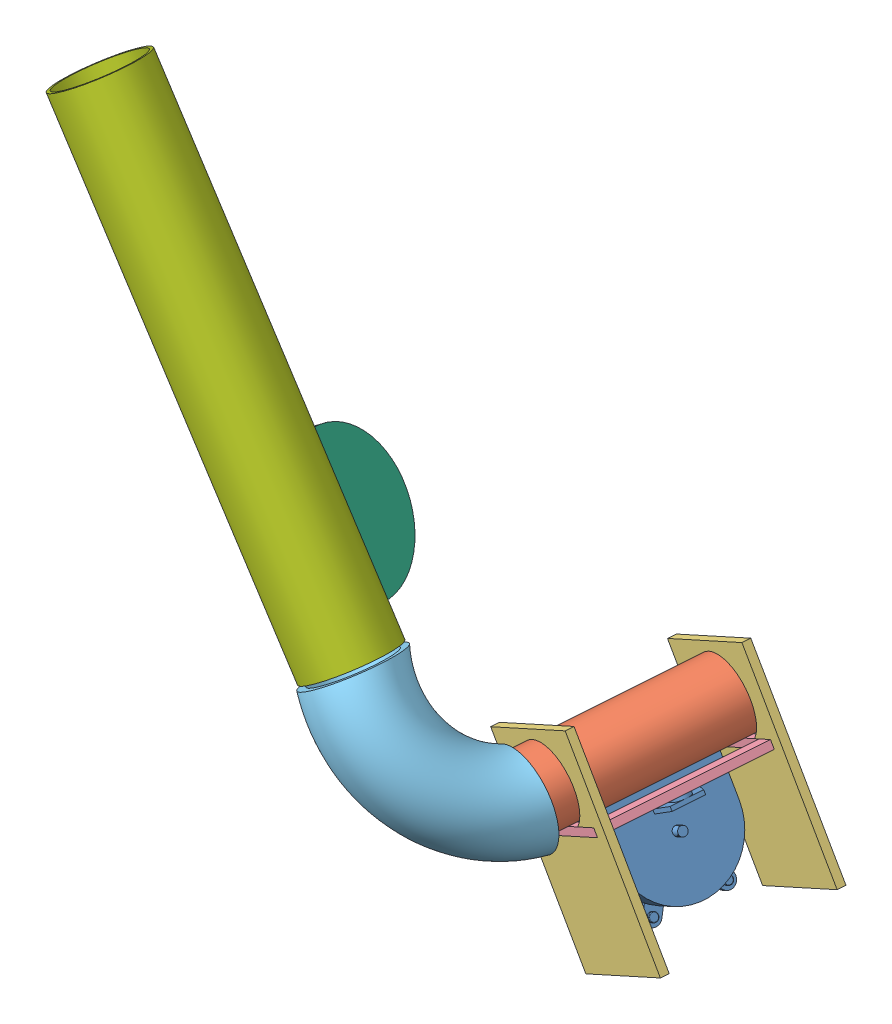
SolidWorks assembly Launcher with Mount, configuration Default. Lengths in mm.
Overall size (379.18 447.74 217.53).
10 component instances, 8 part files, 15 mates.
Components (placement in the parent):
- ToyMotor-1: ToyMotor [Default] at (-45.9782 -159.2587 254.8409) x (0.174213 0.096324 -0.979985) z (0.847546 0.491989 0.199027) size (86.36 71.3 78.87)
- PVC_4.7in_cut-1: PVC_4.7in_cut [Default] at (-55.2346 -115.3565 195.3056) x (0.651296 0.735156 0.188041) z (0.738555 -0.67102 0.065338) size (48.26 121.92 45.73)
- launch_side-2: launch_side [Default] at (-39.1124 -145.2 200.422) x (0.501313 -0.865256 0.004072) z (0.847546 0.491989 0.199027) size (127 5.08 76.2)
- motor_mount-1: motor_mount [Default] at (-55.587 -139.0283 247.3456) x (0.174213 0.096324 -0.979985) z (-0.847546 -0.491989 -0.199027) size (106.68 5.08 60.96)
- launch_side-3: launch_side [Default] at (-56.8124 -154.9865 299.9885) x (0.501313 -0.865256 0.004072) z (0.847546 0.491989 0.199027) size (127 5.08 76.2)
- PVC_Elbow-1: PVC_Elbow [Default] at (-138.237 -56.2898 366.0847) x (-0.174213 -0.096324 0.979985) z (0.566754 -0.823649 0.019795) size (84.68 57.4 121.01)
- PitcherRelease-1: PitcherRelease [Default] at (-236.8906 87.0812 362.6391) x (-0.804731 -0.548265 0.227627) z (0.566754 -0.823649 0.019795) size (64.07 118.35 304.8)
  - genevaWheel-1: genevaWheel [Default] at (2.9948 41.2379 111.0753) x (0 0 1) z (-1 0 0) size (88.9 88.9 5.33)
  - pvc-1: pvc [Default] at (0 0 19.2277) size (54.86 54.86 304.8)
  - pingPongBall-1: pingPongBall [Default] at (0 0 92.2827) x (0.56225 -0.47071 0.679932) z (-0.390358 0.573768 0.720008) size (38.1 38.1 38.1)
Mates (geometry in assembly coordinates):
- Width1: width anti-aligned: plane of ToyMotor-1 through (-36.9962 -153.8739 293.2531) normal (-0.174213 -0.096324 0.979985); plane of ToyMotor-1 through (-24.6062 -147.0233 223.5566) normal (0.174213 0.096324 -0.979985); plane of PVC_4.7in_cut-1 through (-55.2346 -115.3565 195.3056) normal (0.174213 0.096324 -0.979985); plane of PVC_4.7in_cut-1 through (-76.4747 -127.1003 314.7854) normal (-0.174213 -0.096324 0.979985)
- Coincident2: coincident anti-aligned: plane of ToyMotor-1 through (-49.8569 -131.6766 293.1487) normal (-0.501313 0.865256 -0.004072); plane of PVC_4.7in_cut-1 through (-82.1748 -150.3147 311.4903) normal (0.501313 -0.865256 0.004072)
- Width4: width anti-aligned: plane of ToyMotor-1 through (-80.3755 -127.3868 283.6092) normal (-0.847546 -0.491989 -0.199027); plane of ToyMotor-1 through (-64.0145 -117.8895 287.4513) normal (0.847546 0.491989 0.199027); cylinder of PVC_4.7in_cut-1 through (-76.4747 -127.1003 314.7854) axis (0.174213 0.096324 -0.979985) radius 20.32
- Width5: width aligned: plane of ToyMotor-1 through (-36.9962 -153.8739 293.2531) normal (-0.174213 -0.096324 0.979985); plane of ToyMotor-1 through (-24.6062 -147.0233 223.5566) normal (0.174213 0.096324 -0.979985); plane of PVC_4.7in_cut-1 through (-76.4747 -127.1003 314.7854) normal (-0.174213 -0.096324 0.979985); plane of PVC_4.7in_cut-1 through (-55.2346 -115.3565 195.3056) normal (0.174213 0.096324 -0.979985)
- Coincident4: coincident aligned: plane of PVC_4.7in_cut-1 through (-55.2346 -115.3565 195.3056) normal (0.174213 0.096324 -0.979985); plane of launch_side-2 through (25.8975 -180.9096 203.2852) normal (0.174213 0.096324 -0.979985)
- Parallel1: parallel anti-aligned: plane of PVC_4.7in_cut-1 through (-82.1748 -150.3147 311.4903) normal (0.501313 -0.865256 0.004072); plane of launch_side-2 through (-102.3523 -108.5117 187.6022) normal (-0.501313 0.865256 -0.004072)
- Coincident7: coincident aligned: cylinder of PVC_4.7in_cut-1 through (-76.4747 -127.1003 314.7854) axis (0.174213 0.096324 -0.979985) radius 24.13; circle of launch_side-2
- Coincident9: coincident anti-aligned: plane of ToyMotor-1 through (-78.1019 -157.8253 272.598) normal (-0.501313 0.865256 -0.004072); plane of motor_mount-1 through (-88.166 -163.5575 293.5723) normal (0.501313 -0.865256 0.004072)
- Coincident10: coincident aligned: plane of launch_side-2 through (25.8975 -180.9096 203.2852) normal (0.174213 0.096324 -0.979985); plane of motor_mount-1 through (-17.9146 -123.29 201.1602) normal (0.174213 0.096324 -0.979985)
- Width7: width anti-aligned: plane of ToyMotor-1 through (-72.1394 -157.561 218.477) normal (-0.847546 -0.491989 -0.199027); plane of ToyMotor-1 through (-28.7051 -135.0969 268.3212) normal (0.847546 0.491989 0.199027); plane of motor_mount-1 through (-17.9146 -123.29 201.1602) normal (0.847546 0.491989 0.199027); plane of motor_mount-1 through (-69.581 -153.2817 189.0275) normal (-0.847546 -0.491989 -0.199027)
- Coincident14: coincident aligned: plane of motor_mount-1 through (-36.4996 -133.5659 305.705) normal (-0.174213 -0.096324 0.979985); plane of launch_side-3 through (7.3125 -191.1855 307.83) normal (-0.174213 -0.096324 0.979985)
- Concentric2: concentric anti-aligned: cylinder of PVC_4.7in_cut-1 through (-76.4747 -127.1003 314.7854) axis (0.174213 0.096324 -0.979985) radius 24.13; cylinder of launch_side-3 through (-72.9346 -125.143 294.8721) axis (-0.174213 -0.096324 0.979985) radius 24.13
- Coincident15: coincident anti-aligned: plane of motor_mount-1 through (-88.166 -163.5575 293.5723) normal (0.501313 -0.865256 0.004072); plane of launch_side-3 through (-105.866 -173.344 393.1389) normal (-0.501313 0.865256 -0.004072)
- Coincident19: coincident anti-aligned: circle of PVC_4.7in_cut-1; circle of PVC_Elbow-1
- Concentric6: concentric aligned: circle of PVC_Elbow-1; circle of PitcherRelease-1/pvc-1
